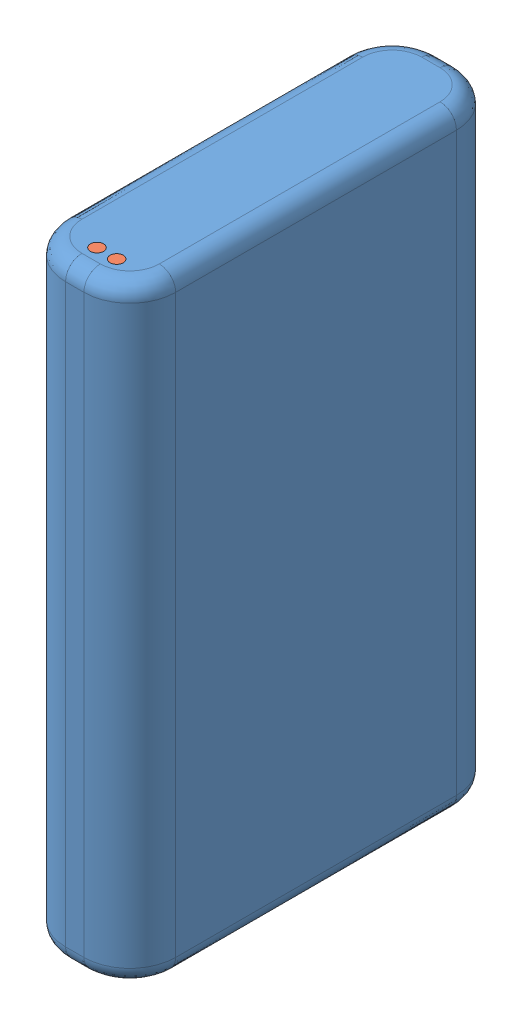
SolidWorks assembly battery_tolerance_shell_ass, configuration Default. Lengths in mm.
Overall size (8.4 46.4 28.4).
2 component instances, 2 part files, 3 mates.
Components (placement in the parent):
- battery_tolerance_shell-1: battery_tolerance_shell [Default] at (20.5501 8.9771 43.7355) size (8.4 46.4 28.4)
- 1100mAh lipo v8-1: 1100mAh lipo v8 [Default] at (24.5501 32.1771 43.7355) x (0 0 1) z (-1 0 0) size (28 46.2 8)
Mates (geometry in assembly coordinates):
- Width1: width anti-aligned: plane of battery_tolerance_shell-1 through (24.7501 55.3771 57.9355) normal (1 0 0); plane of 1100mAh lipo v8-1 through (16.3501 55.3771 57.9355) normal (-1 0 0); plane of battery_tolerance_shell-1 through (16.5501 29.2197 43.7355) normal (-1 0 0); plane of 1100mAh lipo v8-1 through (24.5501 29.2197 43.7355) normal (1 0 0)
- Width2: width anti-aligned: plane of battery_tolerance_shell-1 through (20.5501 8.9771 43.7355) normal (0 -1 0); plane of 1100mAh lipo v8-1 through (20.5501 55.3771 43.7355) normal (0 1 0); plane of battery_tolerance_shell-1 through (24.5501 55.1771 57.7355) normal (0 1 0); plane of 1100mAh lipo v8-1 through (24.5501 9.1771 29.7355) normal (0 -1 0)
- Width3: width anti-aligned: plane of battery_tolerance_shell-1 through (16.3501 55.3771 29.5355) normal (0 0 -1); plane of 1100mAh lipo v8-1 through (16.3501 55.3771 57.9355) normal (0 0 1); plane of battery_tolerance_shell-1 through (24.5501 9.1771 57.7355) normal (0 0 1); plane of 1100mAh lipo v8-1 through (24.5501 49.2623 29.7355) normal (0 0 -1)
